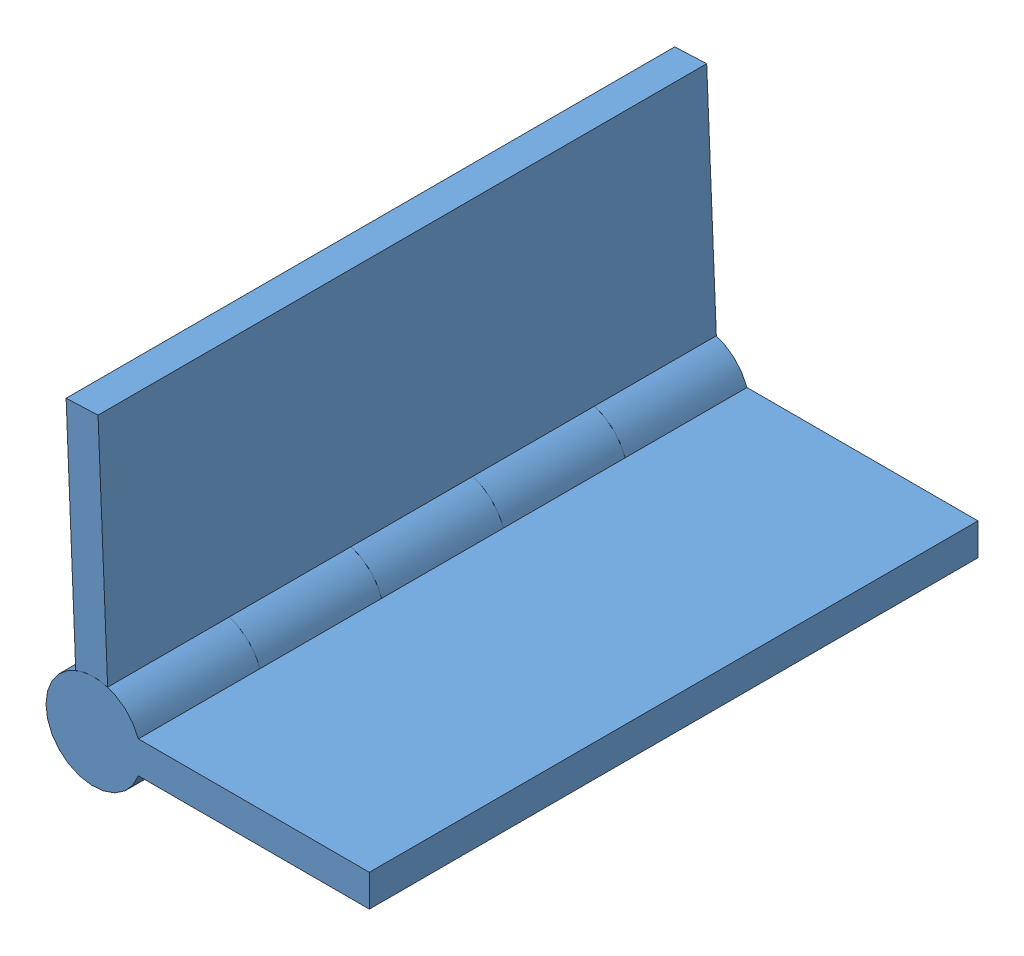
SolidWorks assembly Hinge, configuration Default. Lengths in mm.
Overall size (55.88 54.59 101.6).
2 component instances, 1 part files, 2 mates.
Components (placement in the parent):
- Hinge-1: Hinge [Default] at (-15.0405 0.8871 -53.5184) size (53.98 15.88 101.6)
- Hinge-2: Hinge [Reverse] at (-15.0405 0.8871 -53.5184) x (-0.041598 0.999134 0) z (0 0 1) size (53.98 15.88 101.6)
Mates (geometry in assembly coordinates):
- Coincident1: coincident anti-aligned: plane of Hinge-1 through (-15.0405 0.8871 27.7616) normal (0 0 -1); plane of Hinge-2 through (-15.0405 0.8871 27.7616) normal (0 0 1)
- Concentric1: concentric aligned: circle of Hinge-1; circle of Hinge-2
